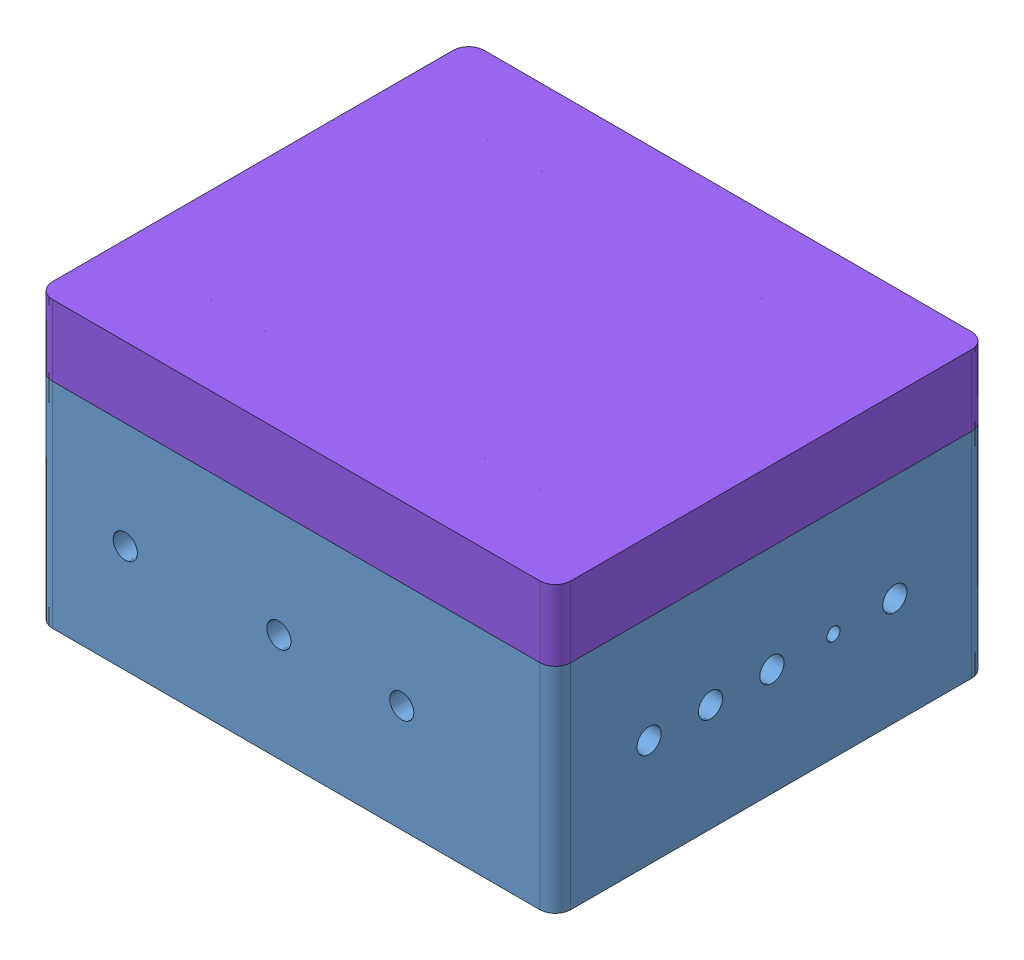
SolidWorks assembly LCA_Baseline_Enclosure_16122020, configuration Default. Lengths in mm.
Overall size (428.6 235.47 356.89).
8 component instances, 8 part files, 22 mates.
Components (placement in the parent):
- 1507 Bottom Tub-1: 1507 Bottom Tub [Default] at (199.2394 311.5225 306.9874) size (428.6 178.19 356.89)
- Back_Plate-1: Back_Plate [Default] at (199.2394 146.6765 306.9874) size (355.6 12.7 254)
- 8961K93_MOUNTING ADAPTERS FOR DIN RAIL-2-1: 8961K93_MOUNTING ADAPTERS FOR DIN RAIL-2 [8961K93] at (377.0394 159.3765 306.9874) x (0 -1 0) z (-1 0 0) size (7.5 35 355.6)
- 8961K107_MOUNTING ADAPTERS FOR DIN RAIL-1: 8961K107_MOUNTING ADAPTERS FOR DIN RAIL [8961K107] at (247.9771 169.3765 281.8198) x (0 1 0) z (-1 0 0) size (8 51.36 75)
- BaselineSpeedgoat-1: BaselineSpeedgoat [Default] at (192.9771 169.3765 270.6428) x (0 0 1) z (-1 0 0) size (200 130 190)
- LoadCellAmplifier-1: LoadCellAmplifier [Default] at (78.9208 237.0128 192.639) x (0 0.999391 -0.034899) z (0 0.034899 0.999391) size (110.24 17.78 89.92)
- 8961K93_MOUNTING ADAPTERS FOR DIN RAIL 6in-1: 8961K93_MOUNTING ADAPTERS FOR DIN RAIL 6in [8961K93] at (35.7408 235.8686 159.8729) x (0 -0.034899 -0.999391) z (1 0 0) size (7.5 35 152.4)
- 1507 Top Tub-1: 1507 Top Tub [Default] at (199.2394 311.5225 306.9874) size (428.6 59.13 356.89)
Mates (geometry in assembly coordinates):
- Coincident1: coincident anti-aligned: plane of 1507 Bottom Tub-1 through (63.4463 146.6765 182.6385) normal (0 1 0); plane of Back_Plate-1 through (199.2394 146.6765 306.9874) normal (0 -1 0)
- Width1: width aligned: plane of Back_Plate-1 through (21.4394 159.3765 179.9874) normal (-1 0 0); plane of 1507 Bottom Tub-1 through (377.0394 159.3765 179.9874) normal (1 0 0); plane of Back_Plate-1 through (1.794 304.6275 306.9874) normal (0.999391 0.034899 0); plane of 1507 Bottom Tub-1 through (396.6848 304.6275 306.9874) normal (-0.999391 0.034899 0)
- Width2: width anti-aligned: plane of Back_Plate-1 through (21.4394 159.3765 433.9874) normal (0 0 1); plane of 1507 Bottom Tub-1 through (21.4394 159.3765 179.9874) normal (0 0 -1); plane of Back_Plate-1 through (199.2394 306.2992 157.4134) normal (0 0.034899 0.999391); plane of 1507 Bottom Tub-1 through (199.2394 306.2992 456.5613) normal (0 0.034899 -0.999391)
- Coincident2: coincident anti-aligned: plane of Back_Plate-1 through (199.2394 159.3765 306.9874) normal (0 1 0); plane of 8961K93_MOUNTING ADAPTERS FOR DIN RAIL-2-1 through (-72.2231 159.3765 293.4874) normal (0 -1 0)
- Width3: width aligned: plane of 8961K93_MOUNTING ADAPTERS FOR DIN RAIL-2-1 through (377.0394 159.3765 306.9874) normal (1 0 0); plane of 1507 Bottom Tub-1 through (21.4394 159.3765 306.9874) normal (-1 0 0); plane of 8961K93_MOUNTING ADAPTERS FOR DIN RAIL-2-1 through (396.6848 304.6275 306.9874) normal (-0.999391 0.034899 0); plane of 1507 Bottom Tub-1 through (1.794 304.6275 306.9874) normal (0.999391 0.034899 0)
- Width4: width anti-aligned: plane of 8961K107_MOUNTING ADAPTERS FOR DIN RAIL-1 through (247.9771 163.0307 281.8198) normal (0 0 -1); plane of 8961K93_MOUNTING ADAPTERS FOR DIN RAIL-2-1 through (247.9771 165.6765 332.1549) normal (0 0 1); plane of 8961K107_MOUNTING ADAPTERS FOR DIN RAIL-1 through (-72.2231 166.8765 324.4874) normal (0 0 1); plane of 8961K93_MOUNTING ADAPTERS FOR DIN RAIL-2-1 through (-72.2231 165.8765 289.4874) normal (0 0 -1)
- Coincident3: coincident anti-aligned: plane of 8961K93_MOUNTING ADAPTERS FOR DIN RAIL-2-1 through (-72.2231 166.8765 320.4874) normal (0 1 0); plane of 8961K107_MOUNTING ADAPTERS FOR DIN RAIL-1 through (247.9771 166.8765 321.4049) normal (0 -1 0)
- Coincident4: coincident anti-aligned: plane of 8961K107_MOUNTING ADAPTERS FOR DIN RAIL-1 through (247.9771 169.3765 282.0698) normal (0 1 0); plane of BaselineSpeedgoat-1 through (192.9771 169.3765 270.6428) normal (0 -1 0)
- Perpendicular1: perpendicular: plane of 1507 Bottom Tub-1 through (199.2394 306.2992 157.4134) normal (0 0.034899 0.999391); plane of BaselineSpeedgoat-1 through (152.9771 299.3765 212.9874) normal (-1 0 0)
- Coincident6: coincident anti-aligned: plane of 8961K107_MOUNTING ADAPTERS FOR DIN RAIL-1 through (247.9771 169.3765 282.0698) normal (0 1 0); plane of BaselineSpeedgoat-1 through (192.9771 169.3765 270.6428) normal (0 -1 0)
- Width6: width anti-aligned: plane of BaselineSpeedgoat-1 through (342.9771 299.3765 402.9874) normal (0 0 1); plane of 1507 Bottom Tub-1 through (192.9771 169.3765 210.9874) normal (0 0 -1); plane of BaselineSpeedgoat-1 through (199.2394 306.2992 157.4134) normal (0 0.034899 0.999391); plane of 1507 Bottom Tub-1 through (199.2394 306.2992 456.5613) normal (0 0.034899 -0.999391)
- Width7: width aligned: plane of 8961K93_MOUNTING ADAPTERS FOR DIN RAIL-2-1 through (-72.2231 166.8765 324.4874) normal (0 0 1); plane of 1507 Bottom Tub-1 through (-72.2231 165.8765 289.4874) normal (0 0 -1); plane of 8961K93_MOUNTING ADAPTERS FOR DIN RAIL-2-1 through (199.2394 306.2992 456.5613) normal (0 0.034899 -0.999391); plane of 1507 Bottom Tub-1 through (199.2394 306.2992 157.4134) normal (0 0.034899 0.999391)
- Width8: width anti-aligned: plane of 8961K107_MOUNTING ADAPTERS FOR DIN RAIL-1 through (210.4771 166.4764 308.0981) normal (-1 0 0); plane of BaselineSpeedgoat-1 through (285.4771 166.4764 308.0981) normal (1 0 0); plane of 8961K107_MOUNTING ADAPTERS FOR DIN RAIL-1 through (342.9771 299.3765 212.9874) normal (1 0 0); plane of BaselineSpeedgoat-1 through (152.9771 299.3765 212.9874) normal (-1 0 0)
- Coincident9: coincident anti-aligned: plane of 1507 Bottom Tub-1 through (199.2394 311.5225 306.9874) normal (0 1 0); plane of 1507 Top Tub-1 through (199.2394 311.5225 306.9874) normal (0 -1 0)
- Width12: width anti-aligned: plane of 1507 Top Tub-1 through (413.538 331.8425 129.797) normal (1 0 0); plane of 1507 Top Tub-1 through (-15.0592 331.8425 486.6911) normal (-1 0 0); plane of 1507 Bottom Tub-1 through (-15.0592 291.2025 129.797) normal (-1 0 0); plane of 1507 Bottom Tub-1 through (413.538 291.2025 486.6911) normal (1 0 0)
- Width13: width anti-aligned: plane of 1507 Top Tub-1 through (-15.0592 331.8425 129.797) normal (0 0 -1); plane of 1507 Top Tub-1 through (413.538 331.8425 486.6911) normal (0 0 1); plane of 1507 Bottom Tub-1 through (-15.0592 291.2025 486.6911) normal (0 0 1); plane of 1507 Bottom Tub-1 through (413.538 291.2025 129.797) normal (0 0 -1)
- Coincident10: coincident anti-aligned: plane of 1507 Bottom Tub-1 through (199.2394 306.2992 157.4134) normal (0 0.034899 0.999391); plane of 8961K93_MOUNTING ADAPTERS FOR DIN RAIL 6in-1 through (485.0033 222.3768 160.344) normal (0 -0.034899 -0.999391)
- Coincident11: coincident anti-aligned: plane of LoadCellAmplifier-1 through (61.1408 181.0459 169.2919) normal (0 -0.034899 -0.999391); plane of 8961K93_MOUNTING ADAPTERS FOR DIN RAIL 6in-1 through (485.0033 249.6221 166.8971) normal (0 0.034899 0.999391)
- Distance1: distance = 50.8 mm aligned: plane of 8961K93_MOUNTING ADAPTERS FOR DIN RAIL 6in-1 through (35.7408 235.8686 159.8729) normal (-1 0 0); plane of 1507 Bottom Tub-1 through (-15.0592 291.2025 129.797) normal (-1 0 0)
- Width16: width anti-aligned: plane of LoadCellAmplifier-1 through (61.1408 291.2147 165.4447) normal (0 0.999391 -0.034899); plane of 8961K93_MOUNTING ADAPTERS FOR DIN RAIL 6in-1 through (61.1408 181.0459 169.2919) normal (0 -0.999391 0.034899); plane of LoadCellAmplifier-1 through (485.0033 218.6061 166.9796) normal (0 -0.999391 0.034899); plane of 8961K93_MOUNTING ADAPTERS FOR DIN RAIL 6in-1 through (485.0033 253.6197 166.7575) normal (0 0.999391 -0.034899)
- Distance3: distance = 25.4 mm aligned: plane of LoadCellAmplifier-1 through (61.1408 237.0128 192.639) normal (-1 0 0); plane of 8961K93_MOUNTING ADAPTERS FOR DIN RAIL 6in-1 through (35.7408 235.8686 159.8729) normal (-1 0 0)
- Distance6: distance = 63.5 mm: line of 8961K93_MOUNTING ADAPTERS FOR DIN RAIL 6in-1 through (188.1408 222.8765 160.3266) axis (-1 0 0); plane of Back_Plate-1 through (199.2394 159.3765 306.9874) normal (0 1 0)
